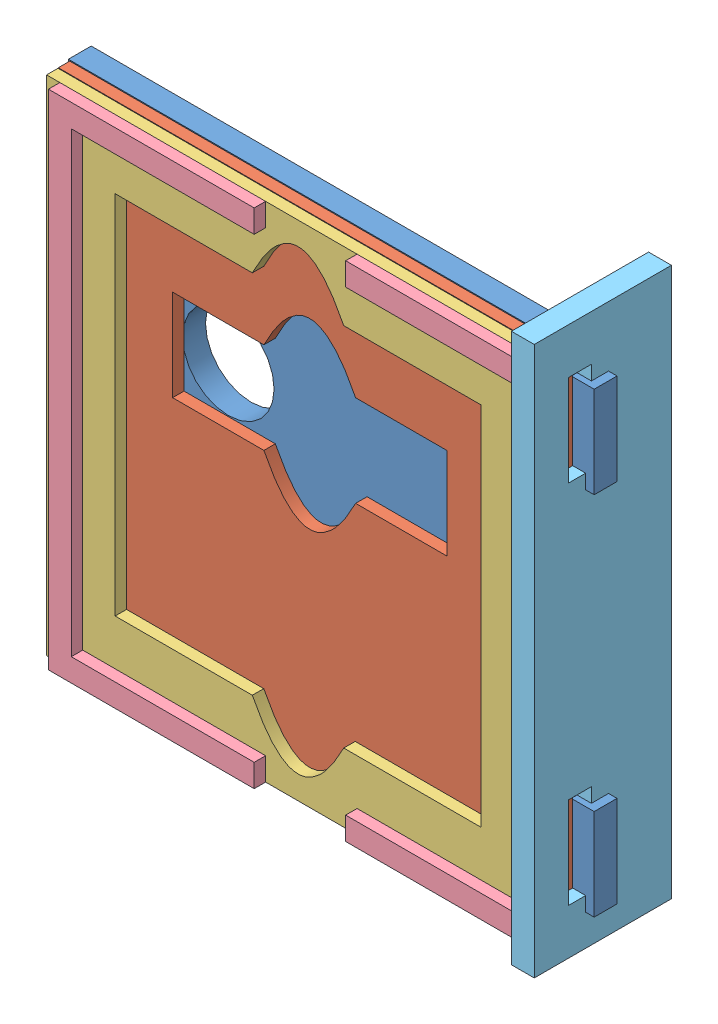
SolidWorks assembly Drawer Assembly, configuration Default. Lengths in mm.
Overall size (146.05 152.4 38.1).
8 component instances, 8 part files, 4 mates.
Components (placement in the parent):
- Drawer Base-1: Drawer Base [Default] at (-56.8074 -63.252 0) size (146.05 139.7 6.35)
- Microscope slide holder-1: Microscope slide holder [Default] at (-56.425 -63.5166 6.35) size (139.7 139.7 3.17)
- 4 inch panel holder-1: 4 inch panel holder [Default] at (-56.5054 -63.6959 9.525) size (139.7 139.7 3.17)
- 5 inch panel holder-1: 5 inch panel holder [Default] at (-52.8128 -63.6959 12.7) size (139.7 139.7 3.17)
- Part1^Drawer Assembly-1: Part1^Drawer Assembly [Default] at origin (virtual)
- Part2^Drawer Assembly-1: Part2^Drawer Assembly [Default] at origin (virtual)
- Part3^Drawer Assembly-1: Part3^Drawer Assembly [Default] at origin (virtual)
- Front-2: Front [Default] at (80.5372 86.8206 20.6299) x (0 -1 0) z (1 0 0) size (152.4 38.1 6.35)
Mates (geometry in assembly coordinates):
- Coincident2: coincident anti-aligned: plane of Drawer Base-1 through (-56.8074 -63.252 6.35) normal (0 0 1); plane of Microscope slide holder-1 through (-56.425 -63.5166 6.35) normal (0 0 -1)
- Coincident3: coincident anti-aligned: plane of Microscope slide holder-1 through (-56.425 -63.5166 9.525) normal (0 0 1); plane of 4 inch panel holder-1 through (-56.5054 -63.6959 9.525) normal (0 0 -1)
- Coincident4: coincident anti-aligned: plane of 4 inch panel holder-1 through (-56.5054 -63.6959 12.7) normal (0 0 1); plane of 5 inch panel holder-1 through (-52.8128 -63.6959 12.7) normal (0 0 -1)
- Coincident6: coincident aligned: plane of 5 inch panel holder-1 through (86.8872 -63.6959 15.875) normal (1 0 0); plane of Front-2 through (86.8872 86.8206 20.6299) normal (1 0 0)
